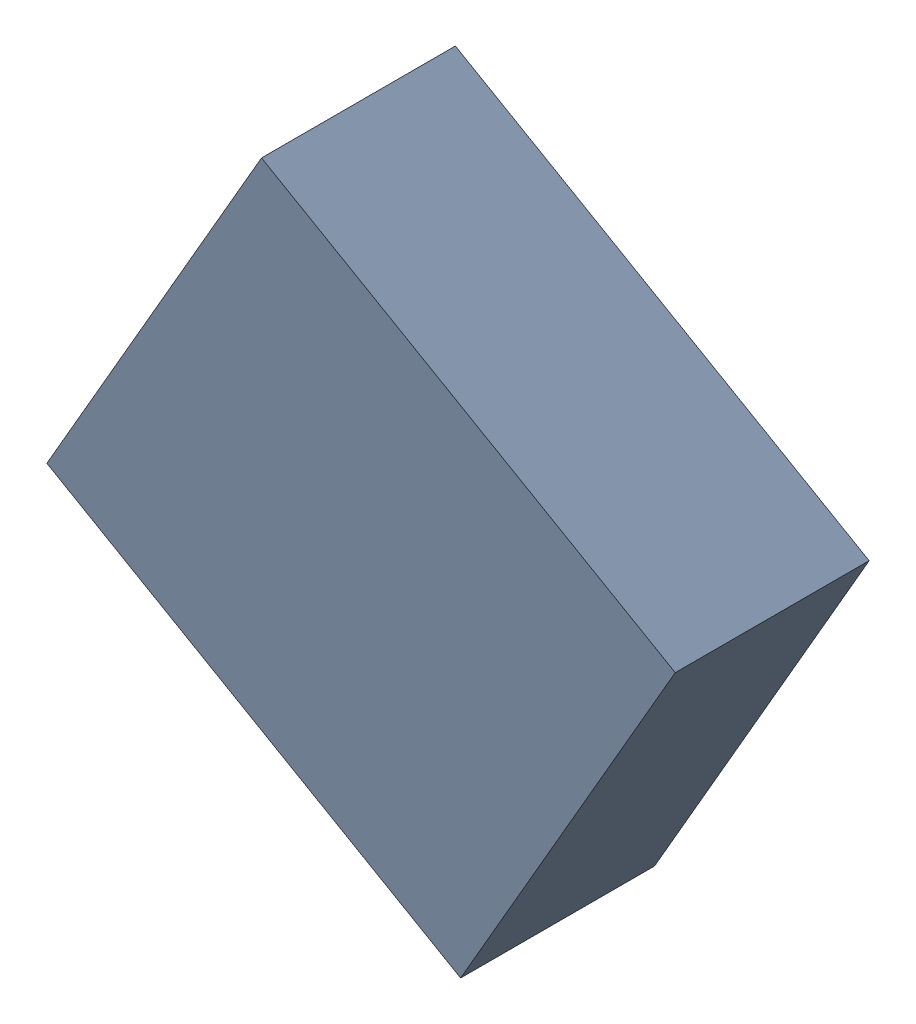
SolidWorks assembly F1_TDA6, configuration Standard. Lengths in mm.
Overall size (4.54 4.41 1.4).
2 component instances, 1 part files, 0 mates.
Components (placement in the parent):
- 885544960-1: 885544960 [Standard] at (-50.1943 27.6532 0) size (4.54 4.41 1.4)
  - Extruded_3-1: Extruded_3 [Standard] at origin size (4.54 4.41 1.4)
